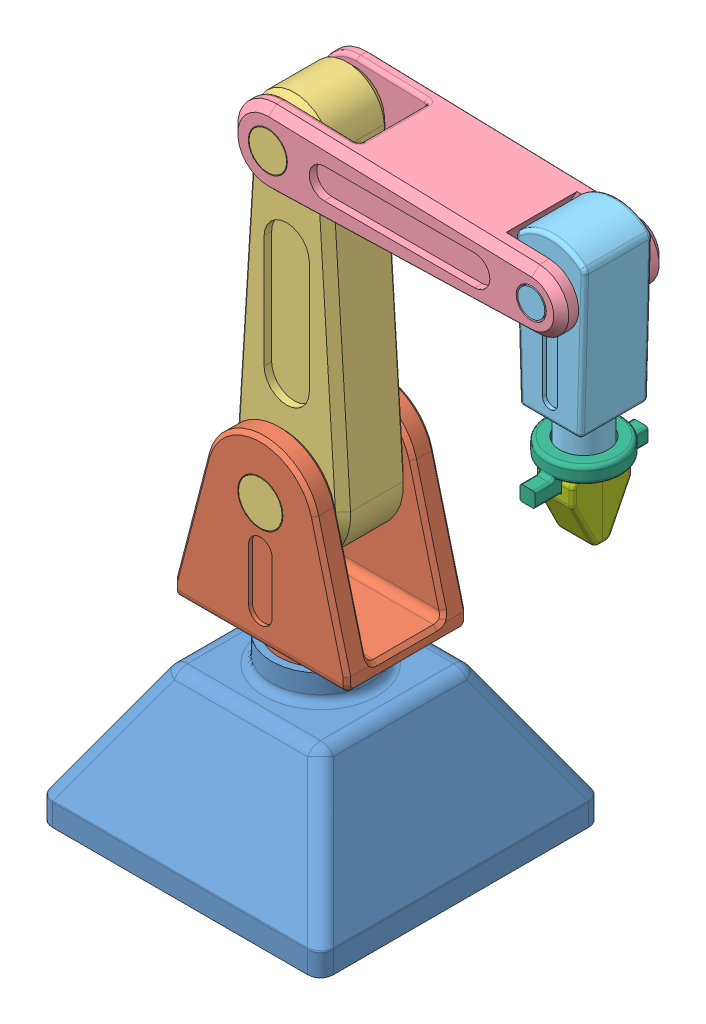
SolidWorks assembly Assem4, configuration Default. Lengths in mm.
Overall size (937.56 1167 375.12).
8 component instances, 7 part files, 21 mates.
Components (placement in the parent):
- Base-1: Base [Default] at (0 405 0) x (0 0 -1) z (1 0 0) size (375.12 215 375.12)
- Link_1-1: Link_1 [Default] at (0 405 0) size (230 280 160)
- Link_2-1: Link_2 [Default] at (0 405 0) x (-1 0 0) z (0 0 -1) size (150 525 160)
- Link_3-1: Link_3 [Default] at (0 405 0) x (-1 0 0) z (0 0 -1) size (440 100 140)
- Link_4-1: Link_4 [Default] at (-50 1155 0) x (0 1 0) z (0 0 -1) size (265 92.4 140)
- Link_5-1: Link_5 [Default] at (-50 1157 0) x (0 1 0) z (0 0 -1) size (42 100 150)
- link_6-1: link_6 [Default] at (-50 1157 0) x (0 1 0) z (0 0 -1) size (90 50 40)
- link_6-2: link_6 [Default] at (750 1157 0) x (0 1 0) z (0 0 1) size (90 50 40)
Mates (geometry in assembly coordinates):
- Coincident3: coincident: point of Base-1; point of assembly
- Concentric1: concentric anti-aligned: cylinder of Base-1 through (0 215 0) axis (0 -1 0) radius 55; cylinder of Link_1-1 through (0 200 0) axis (0 1 0) radius 55
- Coincident5: coincident anti-aligned: plane of Base-1 through (0 200 0) normal (0 1 0); plane of Link_1-1 through (0 200 0) normal (0 -1 0)
- Concentric2: concentric anti-aligned: cylinder of Link_1-1 through (0 405 -80) axis (0 0 1) radius 30; cylinder of Link_2-1 through (0 405 162.0244) axis (0 0 -1) radius 29
- Coincident6: coincident aligned: plane of Link_1-1 through (-115 240 -80) normal (0 0 -1); plane of Link_2-1 through (0 405 -80) normal (0 0 -1)
- Concentric3: concentric anti-aligned: cylinder of Link_2-1 through (0 805 -70) axis (0 0 1) radius 25; cylinder of Link_3-1 through (0 805 521.2206) axis (0 0 -1) radius 26
- Coincident7: coincident aligned: plane of Link_2-1 through (0 805 70) normal (0 0 1); plane of Link_3-1 through (0 805 70) normal (0 0 1)
- Concentric4: concentric aligned: cylinder of Link_3-1 through (350 805 -521.2206) axis (0 0 1) radius 20; cylinder of Link_4-1 through (350 805 -120.9117) axis (0 0 1) radius 18
- Coincident8: coincident aligned: plane of Link_3-1 through (0 805 -70) normal (0 0 -1); plane of Link_4-1 through (350 1155 -70) normal (0 0 -1)
- Concentric5: concentric anti-aligned: cylinder of Link_4-1 through (350 605 0) axis (0 1 0) radius 30; cylinder of Link_5-1 through (350 617 0) axis (0 -1 0) radius 32
- Coincident9: coincident anti-aligned: plane of Link_4-1 through (350 605 0) normal (0 -1 0); plane of Link_5-1 through (350 605 0) normal (0 1 0)
- Coincident10: coincident anti-aligned: plane of Link_5-1 through (-50 575 0) normal (0 -1 0); plane of link_6-1 through (-50 575 40) normal (0 1 0)
- Coincident11: coincident anti-aligned: plane of Link_5-1 through (360 575 75) normal (1 0 0); plane of link_6-1 through (360 1157 40) normal (-1 0 0)
- Parallel1: parallel aligned: plane of Base-1; plane of Link_1-1
- Parallel2: parallel aligned: plane of Link_1-1; plane of Link_2-1
- Perpendicular1: perpendicular: plane of Link_2-1; plane of Link_3-1 through (273.4283 785 -66.7979) normal (0 1 0)
- Perpendicular2: perpendicular: plane of Link_3-1 through (273.4283 785 -66.7979) normal (0 1 0); plane of Link_4-1
- Parallel5: parallel aligned: plane of Link_4-1; plane of Link_5-1
- Coincident17: coincident aligned: plane of Link_5-1; plane of link_6-1
- Coincident22: coincident anti-aligned: plane of Base-1 through (-159.4054 0 167.5111) normal (0 -1 0)
- Parallel8: parallel anti-aligned: plane of Base-1 through (-169.282 0 -186.6025) normal (0 0 -1)
